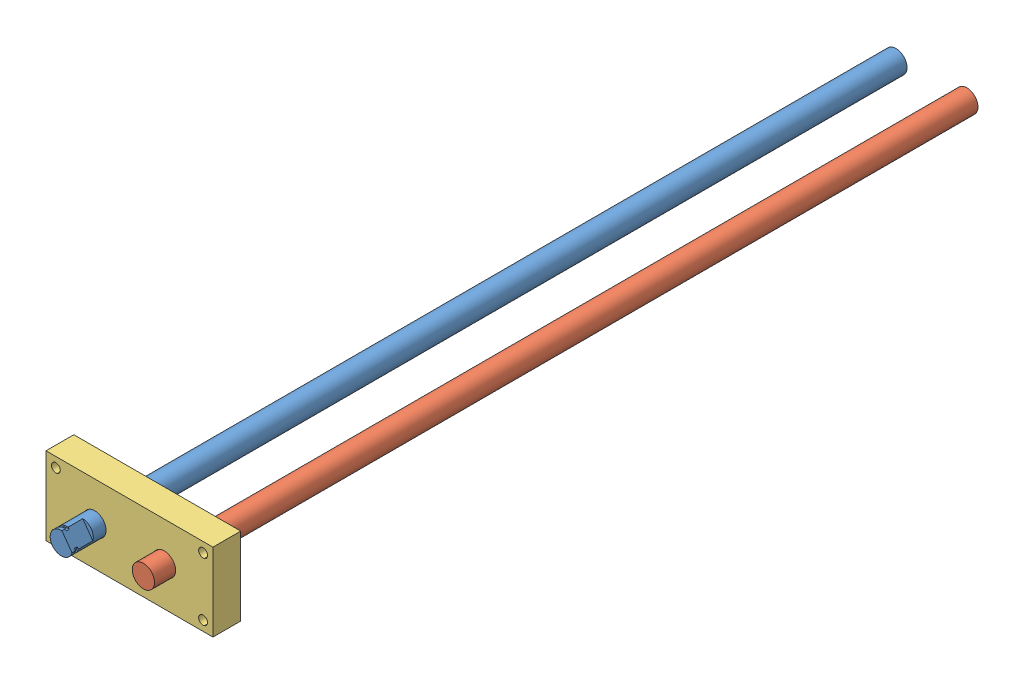
SolidWorks assembly ROBOT WLH, configuration Default. Lengths in mm.
Overall size (60 28 300.5).
3 component instances, 3 part files, 10 mates.
Components (placement in the parent):
- tige filetee-1: tige filetee [Default] at (62.8942 191.6345 167.4136) x (0.579879 -0.814702 0) z (0 0 1) size (8 8 300)
- tige lisse-1: tige lisse [Default] at (87.8942 191.6345 155.4136) x (0.797442 0.603396 0) z (0 0 1) size (8 8 296)
- jot3a guidage-1: jot3a guidage [Default] at (75.3942 191.6345 480.4136) x (1 0 0) z (0 0 -1) size (60 28 10)
Mates (geometry in assembly coordinates):
- Concentric24: concentric anti-aligned: cylinder of Servo motor-4 through (112.8942 201.6345 372.4003) axis (0 0 1) radius 2.9; cylinder of CHADENBATRETCHADEN-1 through (112.8942 201.6345 387.9003) axis (0 0 -1) radius 1.6
- Coincident85: coincident anti-aligned: plane of Servo motor-4 through (112.8942 202.5345 377.9003) normal (0 0 1); plane of CHADENBATRETCHADEN-1 through (167.8277 306.3734 377.9003) normal (0 0 -1)
- Coincident86: coincident anti-aligned: plane of CHADENBATRETCHADEN-1 through (167.8277 306.3734 377.9003) normal (0 0 -1); plane of CHADEN KAABET-1 through (123.3248 257.1605 377.9003) normal (0 0 1)
- Concentric25: concentric anti-aligned: cylinder of CHADENBATRETCHADEN-1 through (134.2252 246.8561 387.9003) axis (0 0 -1) radius 1.6; cylinder of CHADEN KAABET-1 through (134.2252 246.8561 362.5003) axis (0 0 1) radius 1.6
- Lock1: lock: unknown of CHADENBATRETCHADEN-1; unknown of CHADEN KAABET-1
- Coincident95: coincident anti-aligned: plane of CHADENBATRETCHADEN-3 through (150.0302 318.2903 355.8495) normal (0 0 -1); plane of CHADEN KAABET-2 through (126.4342 265.3592 355.8495) normal (0 0 1)
- Concentric29: concentric aligned: cylinder of CHADENBATRETCHADEN-3 through (133.2986 252.022 297.3495) axis (0 0 1) radius 1.6; cylinder of CHADEN KAABET-2 through (133.2986 252.022 340.4495) axis (0 0 1) radius 1.6
- Lock2: lock: unknown of CHADENBATRETCHADEN-3; unknown of CHADEN KAABET-2
- Concentric33: concentric anti-aligned: cylinder of tige lisse-1 through (87.8942 191.6345 442.9136) axis (0 0 -1) radius 4; cylinder of jot3a guidage-1 through (87.8942 191.6345 470.4136) axis (0 0 1) radius 4.1
- Concentric34: concentric anti-aligned: cylinder of tige filetee-1 through (62.8942 191.6345 492.4136) axis (0 0 -1) radius 4; cylinder of jot3a guidage-1 through (62.8942 191.6345 470.4136) axis (0 0 1) radius 4.1
